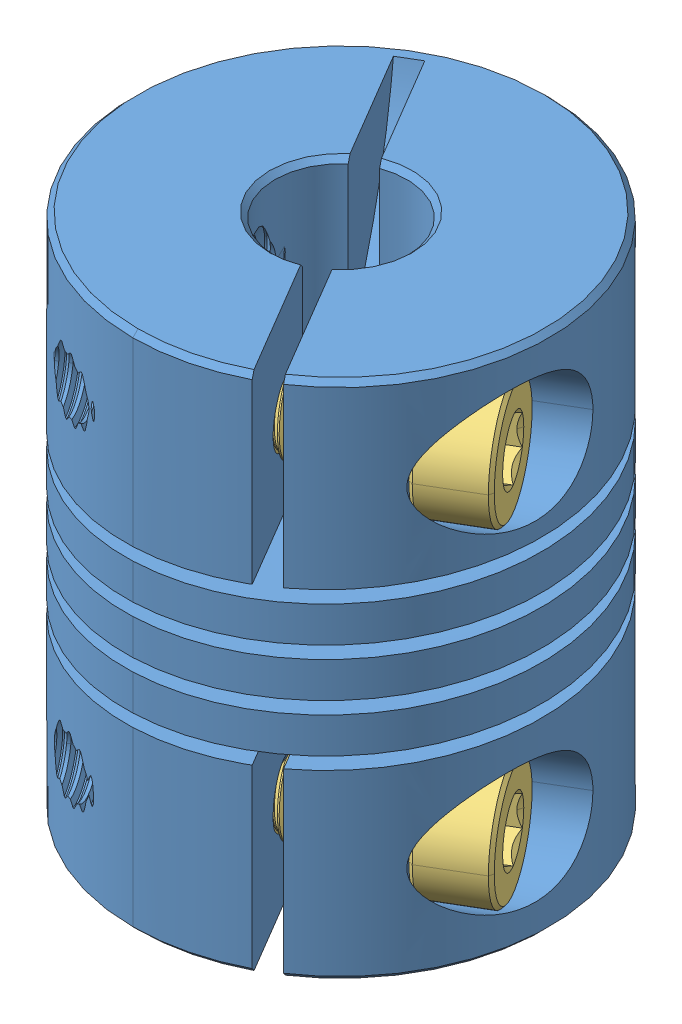
SolidWorks assembly 4002-0008-0250 assembly.STEP, configuration Default. Lengths in mm.
Overall size (21.33 25 20.21).
5 component instances, 3 part files, 0 mates.
Components (placement in the parent):
- 4002-0008-0250.STEP-1: 4002-0008-0250.STEP [Default] at (-19.5633 12.9737 1.5092) size (20.86 25 20)
- 4002 series set-screw_91390A112.STEP-1: 4002 series set-screw_91390A112.STEP [Default] at (-24.9938 21.9237 4.7208) x (0.501173 0.175145 0.847437) z (-0.860742 0 0.509041) size (4.01 4.01 6.01)
- 4002 series set-screw_91390A112.STEP-2: 4002 series set-screw_91390A112.STEP [Default] at (-25.7402 4.0237 5.1621) x (0.237258 0.884739 0.401181) z (-0.860742 0 0.509041) size (4.01 4.01 6.01)
- 4002 series pinch bolt_91290A115.STEP-1: 4002 series pinch bolt_91290A115.STEP [Default] at (-21.2587 20.8987 9.3488) x (0.509041 0 0.860742) z (-0.860742 0 0.509041) size (5.5 5.5 13.01)
- 4002 series pinch bolt_91290A115.STEP-2: 4002 series pinch bolt_91290A115.STEP [Default] at (-21.2587 5.0487 9.3488) x (0.509041 0 0.860742) z (-0.860742 0 0.509041) size (5.5 5.5 13.01)
